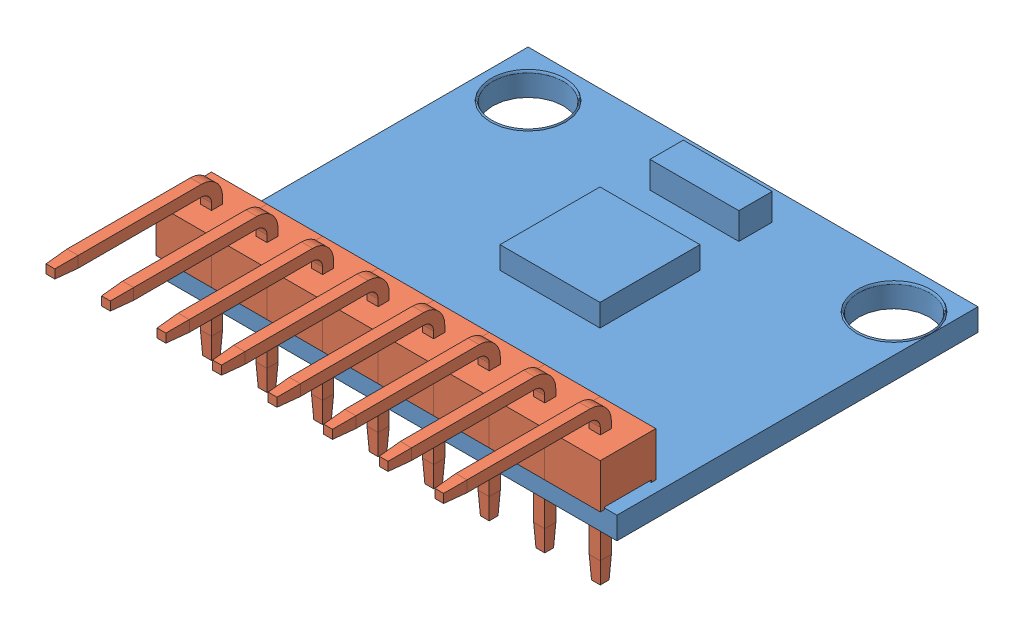
SolidWorks assembly GY521, configuration Predeterminado. Lengths in mm.
Overall size (20.52 65.96 22.5).
9 component instances, 2 part files, 3 mates.
Components (placement in the parent):
- Placa_GY521-1: Placa_GY521 [Predeterminado] at (0.1306 -0.272 0) size (20.27 65.96 16.25)
- PIN_90deg-1: PIN_90deg [Predeterminado] at (-9.1926 0.728 6.9495) x (-1 0 0) z (0 0 -1) size (2.5 7.15 8.5)
- PIN_90deg-2: PIN_90deg [Predeterminado] at (-6.6926 0.728 6.9495) x (-1 0 0) z (0 0 -1) size (2.5 7.15 8.5)
- PIN_90deg-3: PIN_90deg [Predeterminado] at (-4.1926 0.728 6.9495) x (-1 0 0) z (0 0 -1) size (2.5 7.15 8.5)
- PIN_90deg-4: PIN_90deg [Predeterminado] at (-1.6926 0.728 6.9495) x (-1 0 0) z (0 0 -1) size (2.5 7.15 8.5)
- PIN_90deg-5: PIN_90deg [Predeterminado] at (0.8074 0.728 6.9495) x (-1 0 0) z (0 0 -1) size (2.5 7.15 8.5)
- PIN_90deg-6: PIN_90deg [Predeterminado] at (3.3074 0.728 6.9495) x (-1 0 0) z (0 0 -1) size (2.5 7.15 8.5)
- PIN_90deg-7: PIN_90deg [Predeterminado] at (5.8074 0.728 6.9495) x (-1 0 0) z (0 0 -1) size (2.5 7.15 8.5)
- PIN_90deg-8: PIN_90deg [Predeterminado] at (8.3074 0.728 6.9495) x (-1 0 0) z (0 0 -1) size (2.5 7.15 8.5)
Mates (geometry in assembly coordinates):
- Coincidente1: coincident anti-aligned: plane of Placa_GY521-1 through (-9.3426 0.728 6.6995) normal (0 0 1); plane of PIN_90deg-1 through (-8.9426 -3.172 6.6995) normal (0 0 -1)
- Coincidente2: coincident anti-aligned: plane of Placa_GY521-1 through (-8.9426 0.728 7.0995) normal (-1 0 0); plane of PIN_90deg-1 through (-8.9426 -3.172 7.1995) normal (1 0 0)
- Coincidente3: coincident anti-aligned: plane of Placa_GY521-1 through (0.1306 0.728 0) normal (0 1 0); plane of PIN_90deg-1 through (-9.1926 0.728 6.9495) normal (0 -1 0)
